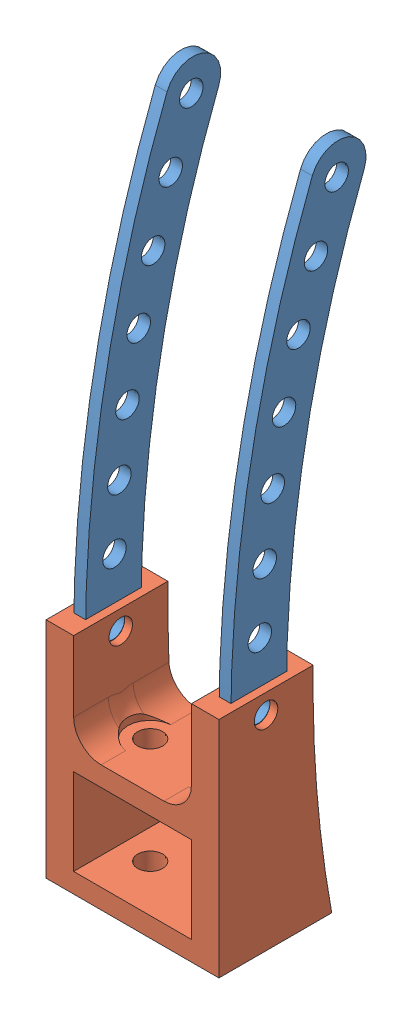
SolidWorks assembly Montagem_Encaixe_Celula_de_Angulo_Variavel, configuration Valor predeterminado. Lengths in mm.
Overall size (44 169.65 41.86).
3 component instances, 2 part files, 5 mates.
Components (placement in the parent):
- Peça_de_angulo-1: Peça_de_angulo [Default] at (0 54.9833 -0.457) x (1 0 0) z (0 0.181887 0.983319) size (3 125.28 19.4)
- Peça_Central-1: Peça_Central [Default] at origin size (44 57 28.72)
- Peça_de_angulo-2: Peça_de_angulo [Default] at (-37 54.9833 -0.457) x (1 0 0) z (0 0.181887 0.983319) size (3 125.28 19.4)
Mates (geometry in assembly coordinates):
- Concêntrico2: concentric aligned: cylinder of Peça_de_angulo-1 through (17 25 -300) axis (1 0 0) radius 292.8327; cylinder of Peça_Central-1 through (17 25 -300) axis (1 0 0) radius 292.8327
- Coincidente1: coincident anti-aligned: plane of Peça_de_angulo-1 through (17 54.9833 -0.457) normal (-1 0 0); plane of Peça_Central-1 through (17 0 0) normal (1 0 0)
- Coincidente2: coincident anti-aligned: plane of Peça_Central-1 through (-17 0 0) normal (-1 0 0); plane of Peça_de_angulo-2 through (-17 54.9833 -0.457) normal (1 0 0)
- Concêntrico3: concentric anti-aligned: cylinder of Peça_Central-1 through (-17 25 -300) axis (-1 0 0) radius 292.8327; cylinder of Peça_de_angulo-2 through (-20 25 -300) axis (1 0 0) radius 292.8327
- Concêntrico4: concentric aligned: cylinder of Peça_de_angulo-1 through (17 132.6249 -19.9698) axis (1 0 0) radius 3; cylinder of Peça_de_angulo-2 through (-20 132.6249 -19.9698) axis (1 0 0) radius 3
